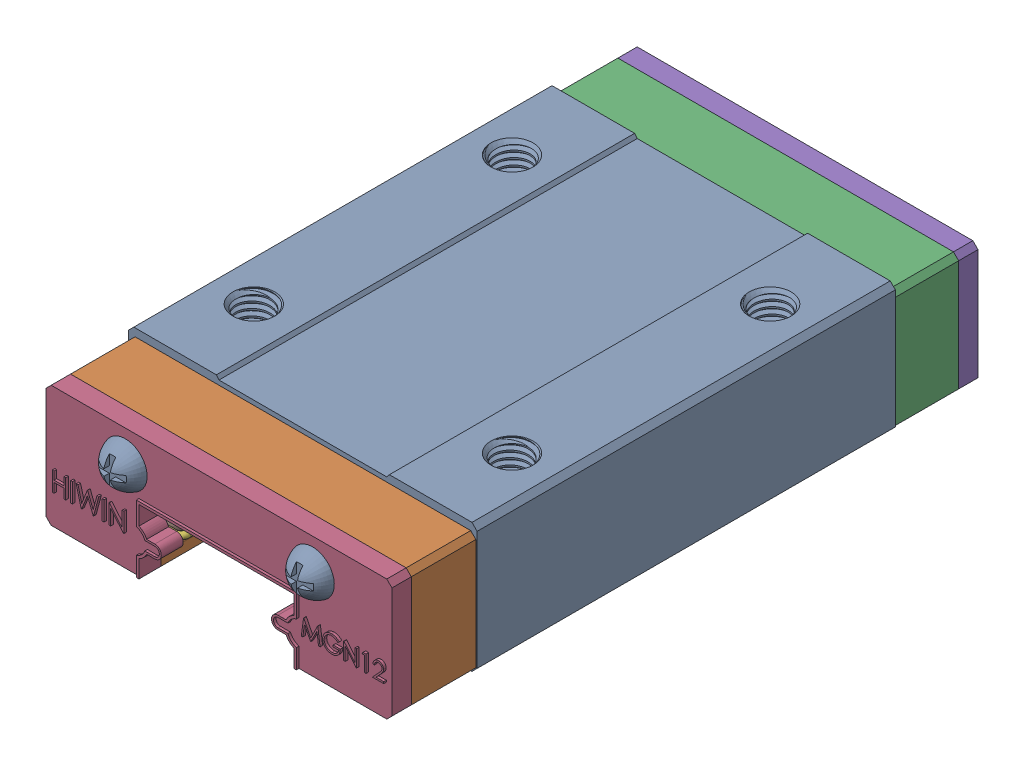
SolidWorks assembly MGN12H, configuration Default. Lengths in mm.
Overall size (27 10.15 48.44).
41 component instances, 5 part files, 88 mates.
Components (placement in the parent):
- MGN12H_Body-1: MGN12H_Body [Default] at origin size (27 10.15 48.44)
- MGN12H_EndCap-1: MGN12H_EndCap [Default] at (0 0 21.2) x (-1 0 0) z (0 0 -1) size (26.8 9.4 5)
- MGN12H_EndCap-2: MGN12H_EndCap [Default] at (0 0 -16.2) x (-1 0 0) z (0 0 -1) size (26.8 9.4 5)
- MGN12H_Seal-1: MGN12H_Seal [Default] at (0 -0.3 22.7) size (26.8 9.4 1.7)
- MGN12H_Seal-2: MGN12H_Seal [Default] at (0 -0.3 -22.7) x (-1 0 0) z (0 0 -1) size (26.8 9.4 1.7)
- MGN12H_Cage-1: MGN12H_Cage [Default] at (-7.7 -2.54 -20.95) x (0 0 1) z (0 1 0) size (42.4 3.25 0.5)
- MGN12H_Cage-2: MGN12H_Cage [Default] at (7.7 -2.79 20.95) x (0 0.005967 -0.999982) z (0 0.999982 0.005967) size (42.4 3.25 0.5)
- MGN12H_Ball-1: MGN12H_Ball [Default] at (-6.48 -2.54 19.51) x (0.839193 0.497101 0.220559) z (-0.329291 0.141699 0.933536) size (2.38 2.38 2.38)
- MGN12H_Ball-2: MGN12H_Ball [Default] at (-6.48 -2.54 17.13) x (0.771669 0.622335 -0.131249) z (0.429679 -0.35795 0.829004) size (2.38 2.38 2.38)
- MGN12H_Ball-3: MGN12H_Ball [Default] at (-6.48 -2.54 14.75) x (0.839193 0.497101 0.220559) z (-0.329291 0.141699 0.933536) size (2.38 2.38 2.38)
- MGN12H_Ball-4: MGN12H_Ball [Default] at (-6.48 -2.54 12.37) x (0.839193 0.497101 0.220559) z (-0.329291 0.141699 0.933536) size (2.38 2.38 2.38)
- MGN12H_Ball-5: MGN12H_Ball [Default] at (-6.48 -2.54 9.99) x (0.839193 0.497101 0.220559) z (-0.329291 0.141699 0.933536) size (2.38 2.38 2.38)
- MGN12H_Ball-6: MGN12H_Ball [Default] at (-6.48 -2.54 7.61) x (0.839193 0.497101 0.220559) z (-0.329291 0.141699 0.933536) size (2.38 2.38 2.38)
- MGN12H_Ball-7: MGN12H_Ball [Default] at (-6.48 -2.54 5.23) x (0.839193 0.497101 0.220559) z (-0.329291 0.141699 0.933536) size (2.38 2.38 2.38)
- MGN12H_Ball-8: MGN12H_Ball [Default] at (-6.48 -2.54 2.85) x (0.839193 0.497101 0.220559) z (-0.329291 0.141699 0.933536) size (2.38 2.38 2.38)
- MGN12H_Ball-9: MGN12H_Ball [Default] at (-6.48 -2.54 0.47) x (0.839193 0.497101 0.220559) z (-0.329291 0.141699 0.933536) size (2.38 2.38 2.38)
- MGN12H_Ball-10: MGN12H_Ball [Default] at (-6.48 -2.54 -1.91) x (0.839193 0.497101 0.220559) z (-0.329291 0.141699 0.933536) size (2.38 2.38 2.38)
- MGN12H_Ball-11: MGN12H_Ball [Default] at (-6.48 -2.54 -4.29) x (0.839193 0.497101 0.220559) z (-0.329291 0.141699 0.933536) size (2.38 2.38 2.38)
- MGN12H_Ball-12: MGN12H_Ball [Default] at (-6.48 -2.54 -6.67) x (0.839193 0.497101 0.220559) z (-0.329291 0.141699 0.933536) size (2.38 2.38 2.38)
- MGN12H_Ball-13: MGN12H_Ball [Default] at (-6.48 -2.54 -9.05) x (0.839193 0.497101 0.220559) z (-0.329291 0.141699 0.933536) size (2.38 2.38 2.38)
- MGN12H_Ball-14: MGN12H_Ball [Default] at (-6.48 -2.54 -11.43) x (0.839193 0.497101 0.220559) z (-0.329291 0.141699 0.933536) size (2.38 2.38 2.38)
- MGN12H_Ball-15: MGN12H_Ball [Default] at (-6.48 -2.54 -13.81) x (0.839193 0.497101 0.220559) z (-0.329291 0.141699 0.933536) size (2.38 2.38 2.38)
- MGN12H_Ball-16: MGN12H_Ball [Default] at (-6.48 -2.54 -16.19) x (0.839193 0.497101 0.220559) z (-0.329291 0.141699 0.933536) size (2.38 2.38 2.38)
- MGN12H_Ball-17: MGN12H_Ball [Default] at (-6.48 -2.54 -19.51) x (-0.170266 0.97688 -0.129289) z (-0.747111 -0.213527 -0.629469) size (2.38 2.38 2.38)
- MGN12H_Ball-18: MGN12H_Ball [Default] at (6.48 -2.54 19.5319) x (-0.170266 0.97688 -0.129289) z (-0.747111 -0.213527 -0.629469) size (2.38 2.38 2.38)
- MGN12H_Ball-19: MGN12H_Ball [Default] at (6.48 -2.54 17.1519) x (-0.170266 0.97688 -0.129289) z (-0.747111 -0.213527 -0.629469) size (2.38 2.38 2.38)
- MGN12H_Ball-20: MGN12H_Ball [Default] at (6.48 -2.54 14.7719) x (-0.170266 0.97688 -0.129289) z (-0.747111 -0.213527 -0.629469) size (2.38 2.38 2.38)
- MGN12H_Ball-21: MGN12H_Ball [Default] at (6.48 -2.54 12.3919) x (-0.170266 0.97688 -0.129289) z (-0.747111 -0.213527 -0.629469) size (2.38 2.38 2.38)
- MGN12H_Ball-22: MGN12H_Ball [Default] at (6.48 -2.54 10.0119) x (-0.170266 0.97688 -0.129289) z (-0.747111 -0.213527 -0.629469) size (2.38 2.38 2.38)
- MGN12H_Ball-23: MGN12H_Ball [Default] at (6.48 -2.54 7.6319) x (-0.170266 0.97688 -0.129289) z (-0.747111 -0.213527 -0.629469) size (2.38 2.38 2.38)
- MGN12H_Ball-24: MGN12H_Ball [Default] at (6.48 -2.54 5.2519) x (-0.170266 0.97688 -0.129289) z (-0.747111 -0.213527 -0.629469) size (2.38 2.38 2.38)
- MGN12H_Ball-25: MGN12H_Ball [Default] at (6.48 -2.54 2.8719) x (-0.170266 0.97688 -0.129289) z (-0.747111 -0.213527 -0.629469) size (2.38 2.38 2.38)
- MGN12H_Ball-26: MGN12H_Ball [Default] at (6.48 -2.54 0.4919) x (-0.170266 0.97688 -0.129289) z (-0.747111 -0.213527 -0.629469) size (2.38 2.38 2.38)
- MGN12H_Ball-27: MGN12H_Ball [Default] at (6.48 -2.54 -1.8881) x (-0.170266 0.97688 -0.129289) z (-0.747111 -0.213527 -0.629469) size (2.38 2.38 2.38)
- MGN12H_Ball-28: MGN12H_Ball [Default] at (6.48 -2.54 -4.2681) x (-0.170266 0.97688 -0.129289) z (-0.747111 -0.213527 -0.629469) size (2.38 2.38 2.38)
- MGN12H_Ball-29: MGN12H_Ball [Default] at (6.48 -2.54 -6.6481) x (-0.170266 0.97688 -0.129289) z (-0.747111 -0.213527 -0.629469) size (2.38 2.38 2.38)
- MGN12H_Ball-30: MGN12H_Ball [Default] at (6.48 -2.54 -9.0281) x (-0.170266 0.97688 -0.129289) z (-0.747111 -0.213527 -0.629469) size (2.38 2.38 2.38)
- MGN12H_Ball-31: MGN12H_Ball [Default] at (6.48 -2.54 -11.4081) x (-0.170266 0.97688 -0.129289) z (-0.747111 -0.213527 -0.629469) size (2.38 2.38 2.38)
- MGN12H_Ball-32: MGN12H_Ball [Default] at (6.48 -2.54 -13.7881) x (-0.170266 0.97688 -0.129289) z (-0.747111 -0.213527 -0.629469) size (2.38 2.38 2.38)
- MGN12H_Ball-33: MGN12H_Ball [Default] at (6.48 -2.54 -16.1681) x (-0.170266 0.97688 -0.129289) z (-0.747111 -0.213527 -0.629469) size (2.38 2.38 2.38)
- MGN12H_Ball-34: MGN12H_Ball [Default] at (6.48 -2.54 -19.5093) x (-0.029751 0.936883 -0.348374) z (-0.95519 -0.129332 -0.266242) size (2.38 2.38 2.38)
Mates (geometry in assembly coordinates):
- Coincident1: coincident anti-aligned: plane of MGN12H_Body-1 through (0 0 16.2) normal (0 0 1); plane of MGN12H_EndCap-1 through (6.48 -2.54 16.2) normal (0 0 -1)
- Coincident2: coincident aligned: plane of MGN12H_Body-1 through (0 0 16.2) normal (0 -1 0); plane of MGN12H_EndCap-1 through (-6 0 16.2) normal (0 -1 0)
- Concentric1: concentric anti-aligned: cylinder of MGN12H_Body-1 through (-6.48 -2.54 16.2) axis (0 0 -1) radius 1.19; cylinder of MGN12H_EndCap-1 through (-6.48 -2.54 16.2) axis (0 0 1) radius 1.19
- Coincident3: coincident anti-aligned: plane of MGN12H_Body-1 through (0 0 -16.2) normal (0 0 -1); plane of MGN12H_EndCap-2 through (6.48 -2.54 -16.2) normal (0 0 1)
- Coincident4: coincident aligned: plane of MGN12H_Body-1 through (0 0 16.2) normal (0 -1 0); plane of MGN12H_EndCap-2 through (-6 0 -21.2) normal (0 -1 0)
- Concentric2: concentric anti-aligned: cylinder of MGN12H_Body-1 through (6.48 -2.54 16.2) axis (0 0 -1) radius 1.19; cylinder of MGN12H_EndCap-2 through (6.48 -2.54 -21.2) axis (0 0 1) radius 1.19
- Coincident5: coincident anti-aligned: plane of MGN12H_EndCap-1 through (6.48 -2.54 21.2) normal (0 0 1); plane of MGN12H_Seal-1 through (0 -0.3 21.2) normal (0 0 -1)
- Coincident6: coincident aligned: plane of MGN12H_EndCap-1 through (-6 0 16.2) normal (0 -1 0); plane of MGN12H_Seal-1 through (0 0 21.2) normal (0 -1 0)
- Coincident7: coincident aligned: plane of MGN12H_EndCap-1 through (-6 -5 16.2) normal (1 0 0); plane of MGN12H_Seal-1 through (-6 -0.3 21.2) normal (1 0 0)
- Coincident8: coincident anti-aligned: plane of MGN12H_EndCap-2 through (6.48 -2.54 -21.2) normal (0 0 -1); plane of MGN12H_Seal-2 through (0 -0.3 -21.2) normal (0 0 1)
- Coincident9: coincident aligned: plane of MGN12H_EndCap-2 through (-6 0 -21.2) normal (0 -1 0); plane of MGN12H_Seal-2 through (0 0 -21.2) normal (0 -1 0)
- Coincident10: coincident aligned: plane of MGN12H_EndCap-2 through (6 -5 -21.2) normal (-1 0 0); plane of MGN12H_Seal-2 through (6 -0.3 -21.2) normal (-1 0 0)
- Distance1: distance = 5.8 mm aligned: plane of MGN12H_Cage-1 through (-7.7 -2.54 -20.95) normal (-1 0 0); plane of MGN12H_Body-1 through (-13.5 0 16.2) normal (-1 0 0)
- Tangent1: tangent anti-aligned: plane of MGN12H_Seal-2 through (0 -0.3 -21.2) normal (0 0 1); cylinder of MGN12H_Cage-1 through (-5.7 -2.54 -20.95) axis (-1 0 0) radius 0.25
- Distance2: distance = 2.54 mm: cylinder of MGN12H_Cage-1 through (-5.2 -2.54 20.95) axis (-1 0 0) radius 0.25; plane of MGN12H_Body-1 through (0 0 16.2) normal (0 -1 0)
- Distance3: distance = 2.54 mm: cylinder of MGN12H_Cage-1 through (-5.7 -2.54 -20.95) axis (-1 0 0) radius 0.25; plane of MGN12H_Body-1 through (0 0 16.2) normal (0 -1 0)
- Distance4: distance = 5.8 mm aligned: plane of MGN12H_Cage-2 through (7.7 -2.79 20.95) normal (1 0 0); plane of MGN12H_Body-1 through (13.5 0 16.2) normal (1 0 0)
- Distance5: distance = 2.54 mm: cylinder of MGN12H_Cage-2 through (5.7 -2.79 20.95) axis (1 0 0) radius 0.25; plane of MGN12H_Body-1 through (0 0 16.2) normal (0 -1 0)
- Distance7: distance = 2.54 mm: plane of MGN12H_Body-1 through (0 0 16.2) normal (0 -1 0); cylinder of MGN12H_Cage-2 through (5.2 -2.54 -20.9493) axis (1 0 0) radius 0.25
- Tangent8: tangent anti-aligned: plane of MGN12H_Seal-1 through (0 -0.3 21.2) normal (0 0 -1); cylinder of MGN12H_Cage-2 through (5.7 -2.79 20.95) axis (1 0 0) radius 0.25
- Concentric3: concentric: cylinder of MGN12H_Body-1 through (-6.48 -2.54 16.2) axis (0 0 -1) radius 1.19; sphere of MGN12H_Ball-1
- Tangent11: tangent anti-aligned: cylinder of MGN12H_Cage-1 through (-5.2 -2.54 20.95) axis (-1 0 0) radius 0.25; sphere of MGN12H_Ball-1
- Concentric4: concentric: cylinder of MGN12H_Body-1 through (-6.48 -2.54 16.2) axis (0 0 -1) radius 1.19; sphere of MGN12H_Ball-2
- Tangent12: tangent anti-aligned: sphere of MGN12H_Ball-1; sphere of MGN12H_Ball-2
- Concentric6: concentric: cylinder of MGN12H_Body-1 through (-6.48 -2.54 16.2) axis (0 0 -1) radius 1.19; sphere of MGN12H_Ball-3
- Tangent13: tangent anti-aligned: sphere of MGN12H_Ball-2; sphere of MGN12H_Ball-3
- Concentric7: concentric: cylinder of MGN12H_Body-1 through (-6.48 -2.54 16.2) axis (0 0 -1) radius 1.19; sphere of MGN12H_Ball-4
- Tangent14: tangent anti-aligned: sphere of MGN12H_Ball-3; sphere of MGN12H_Ball-4
- Concentric8: concentric: cylinder of MGN12H_Body-1 through (-6.48 -2.54 16.2) axis (0 0 -1) radius 1.19; sphere of MGN12H_Ball-5
- Tangent16: tangent anti-aligned: sphere of MGN12H_Ball-4; sphere of MGN12H_Ball-5
- Concentric9: concentric: cylinder of MGN12H_Body-1 through (-6.48 -2.54 16.2) axis (0 0 -1) radius 1.19; sphere of MGN12H_Ball-6
- Tangent17: tangent anti-aligned: sphere of MGN12H_Ball-5; sphere of MGN12H_Ball-6
- Concentric10: concentric: cylinder of MGN12H_Body-1 through (-6.48 -2.54 16.2) axis (0 0 -1) radius 1.19; sphere of MGN12H_Ball-7
- Tangent18: tangent anti-aligned: sphere of MGN12H_Ball-6; sphere of MGN12H_Ball-7
- Concentric11: concentric: cylinder of MGN12H_Body-1 through (-6.48 -2.54 16.2) axis (0 0 -1) radius 1.19; sphere of MGN12H_Ball-8
- Tangent19: tangent anti-aligned: sphere of MGN12H_Ball-7; sphere of MGN12H_Ball-8
- Concentric12: concentric: cylinder of MGN12H_Body-1 through (-6.48 -2.54 16.2) axis (0 0 -1) radius 1.19; sphere of MGN12H_Ball-9
- Tangent20: tangent anti-aligned: sphere of MGN12H_Ball-8; sphere of MGN12H_Ball-9
- Concentric13: concentric: cylinder of MGN12H_Body-1 through (-6.48 -2.54 16.2) axis (0 0 -1) radius 1.19; sphere of MGN12H_Ball-10
- Tangent21: tangent anti-aligned: sphere of MGN12H_Ball-9; sphere of MGN12H_Ball-10
- Concentric14: concentric: cylinder of MGN12H_Body-1 through (-6.48 -2.54 16.2) axis (0 0 -1) radius 1.19; sphere of MGN12H_Ball-11
- Tangent22: tangent anti-aligned: sphere of MGN12H_Ball-10; sphere of MGN12H_Ball-11
- Concentric15: concentric: cylinder of MGN12H_Body-1 through (-6.48 -2.54 16.2) axis (0 0 -1) radius 1.19; sphere of MGN12H_Ball-12
- Tangent23: tangent anti-aligned: sphere of MGN12H_Ball-11; sphere of MGN12H_Ball-12
- Concentric16: concentric: cylinder of MGN12H_Body-1 through (-6.48 -2.54 16.2) axis (0 0 -1) radius 1.19; sphere of MGN12H_Ball-13
- Tangent24: tangent anti-aligned: sphere of MGN12H_Ball-12; sphere of MGN12H_Ball-13
- Concentric17: concentric: cylinder of MGN12H_Body-1 through (-6.48 -2.54 16.2) axis (0 0 -1) radius 1.19; sphere of MGN12H_Ball-14
- Tangent25: tangent anti-aligned: sphere of MGN12H_Ball-13; sphere of MGN12H_Ball-14
- Concentric18: concentric: cylinder of MGN12H_Body-1 through (-6.48 -2.54 16.2) axis (0 0 -1) radius 1.19; sphere of MGN12H_Ball-15
- Tangent26: tangent anti-aligned: sphere of MGN12H_Ball-14; sphere of MGN12H_Ball-15
- Concentric19: concentric: cylinder of MGN12H_EndCap-2 through (-6.48 -2.54 -21.2) axis (0 0 1) radius 1.19; sphere of MGN12H_Ball-16
- Tangent27: tangent anti-aligned: sphere of MGN12H_Ball-15; sphere of MGN12H_Ball-16
- Concentric20: concentric: cylinder of MGN12H_EndCap-2 through (-6.48 -2.54 -21.2) axis (0 0 1) radius 1.19; sphere of MGN12H_Ball-17
- Tangent28: tangent anti-aligned: cylinder of MGN12H_Cage-1 through (-5.7 -2.54 -20.95) axis (-1 0 0) radius 0.25; sphere of MGN12H_Ball-17
- Concentric21: concentric: cylinder of MGN12H_Body-1 through (6.48 -2.54 16.2) axis (0 0 -1) radius 1.19; sphere of MGN12H_Ball-18
- Tangent29: tangent anti-aligned: cylinder of MGN12H_Cage-2 through (5.7 -2.79 20.95) axis (1 0 0) radius 0.25; sphere of MGN12H_Ball-18
- Concentric22: concentric: cylinder of MGN12H_Body-1 through (6.48 -2.54 16.2) axis (0 0 -1) radius 1.19; sphere of MGN12H_Ball-19
- Tangent30: tangent anti-aligned: sphere of MGN12H_Ball-18; sphere of MGN12H_Ball-19
- Concentric23: concentric: cylinder of MGN12H_Body-1 through (6.48 -2.54 16.2) axis (0 0 -1) radius 1.19; sphere of MGN12H_Ball-20
- Tangent31: tangent anti-aligned: sphere of MGN12H_Ball-19; sphere of MGN12H_Ball-20
- Concentric24: concentric: cylinder of MGN12H_Body-1 through (6.48 -2.54 16.2) axis (0 0 -1) radius 1.19; sphere of MGN12H_Ball-21
- Tangent32: tangent anti-aligned: sphere of MGN12H_Ball-20; sphere of MGN12H_Ball-21
- Concentric25: concentric: cylinder of MGN12H_Body-1 through (6.48 -2.54 16.2) axis (0 0 -1) radius 1.19; sphere of MGN12H_Ball-22
- Tangent33: tangent anti-aligned: sphere of MGN12H_Ball-21; sphere of MGN12H_Ball-22
- Concentric26: concentric: cylinder of MGN12H_Body-1 through (6.48 -2.54 16.2) axis (0 0 -1) radius 1.19; sphere of MGN12H_Ball-23
- Tangent34: tangent anti-aligned: sphere of MGN12H_Ball-22; sphere of MGN12H_Ball-23
- Concentric27: concentric: cylinder of MGN12H_Body-1 through (6.48 -2.54 16.2) axis (0 0 -1) radius 1.19; sphere of MGN12H_Ball-24
- Tangent36: tangent anti-aligned: sphere of MGN12H_Ball-23; sphere of MGN12H_Ball-24
- Concentric28: concentric: cylinder of MGN12H_Body-1 through (6.48 -2.54 16.2) axis (0 0 -1) radius 1.19; sphere of MGN12H_Ball-25
- Tangent37: tangent anti-aligned: sphere of MGN12H_Ball-24; sphere of MGN12H_Ball-25
- Concentric29: concentric: cylinder of MGN12H_Body-1 through (6.48 -2.54 16.2) axis (0 0 -1) radius 1.19; sphere of MGN12H_Ball-26
- Tangent38: tangent anti-aligned: sphere of MGN12H_Ball-25; sphere of MGN12H_Ball-26
- Concentric30: concentric: cylinder of MGN12H_Body-1 through (6.48 -2.54 16.2) axis (0 0 -1) radius 1.19; sphere of MGN12H_Ball-27
- Tangent39: tangent anti-aligned: sphere of MGN12H_Ball-26; sphere of MGN12H_Ball-27
- Concentric31: concentric: cylinder of MGN12H_Body-1 through (6.48 -2.54 16.2) axis (0 0 -1) radius 1.19; sphere of MGN12H_Ball-28
- Tangent40: tangent anti-aligned: sphere of MGN12H_Ball-27; sphere of MGN12H_Ball-28
- Concentric32: concentric: cylinder of MGN12H_Body-1 through (6.48 -2.54 16.2) axis (0 0 -1) radius 1.19; sphere of MGN12H_Ball-29
- Tangent41: tangent anti-aligned: sphere of MGN12H_Ball-28; sphere of MGN12H_Ball-29
- Concentric33: concentric: cylinder of MGN12H_Body-1 through (6.48 -2.54 16.2) axis (0 0 -1) radius 1.19; sphere of MGN12H_Ball-30
- Tangent42: tangent anti-aligned: sphere of MGN12H_Ball-29; sphere of MGN12H_Ball-30
- Concentric35: concentric: cylinder of MGN12H_Body-1 through (6.48 -2.54 16.2) axis (0 0 -1) radius 1.19; sphere of MGN12H_Ball-31
- Tangent43: tangent anti-aligned: sphere of MGN12H_Ball-30; sphere of MGN12H_Ball-31
- Concentric36: concentric: cylinder of MGN12H_Body-1 through (6.48 -2.54 16.2) axis (0 0 -1) radius 1.19; sphere of MGN12H_Ball-32
- Tangent44: tangent anti-aligned: sphere of MGN12H_Ball-31; sphere of MGN12H_Ball-32
- Concentric37: concentric: cylinder of MGN12H_EndCap-2 through (6.48 -2.54 -21.2) axis (0 0 1) radius 1.19; sphere of MGN12H_Ball-33
- Tangent45: tangent anti-aligned: sphere of MGN12H_Ball-32; sphere of MGN12H_Ball-33
- Concentric38: concentric: cylinder of MGN12H_EndCap-2 through (6.48 -2.54 -21.2) axis (0 0 1) radius 1.19; sphere of MGN12H_Ball-34
- Tangent46: tangent anti-aligned: cylinder of MGN12H_Cage-2 through (5.2 -2.54 -20.9493) axis (1 0 0) radius 0.25; sphere of MGN12H_Ball-34
